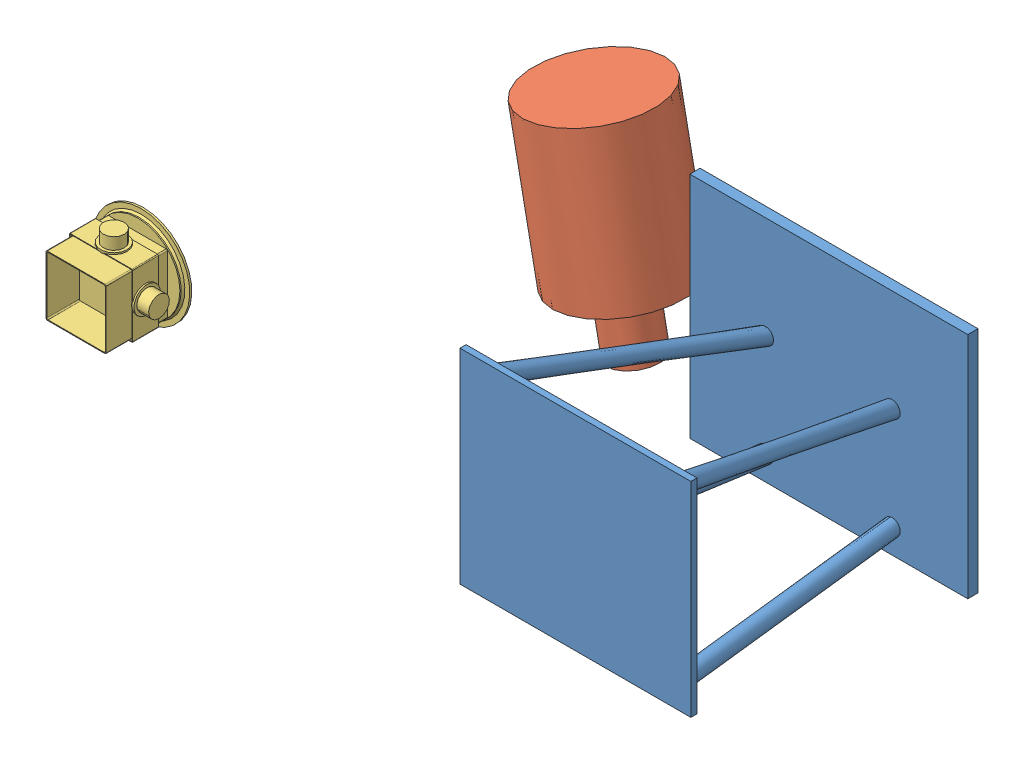
SolidWorks assembly Сборка1, configuration Default. Lengths in mm.
Overall size (1516.53 640.42 1145.63).
3 component instances, 3 part files, 2 mates.
Components (placement in the parent):
- Столик_3-1: Столик_3 [Default] at (296.4527 401.5534 802.29) size (680 560 645)
- Neutron_generator-1: Neutron_generator [Default] at (-428.6514 597.3112 32.29) x (0.748489 0.149038 0.646183) z (0.195284 -0.980747 0) size (300 300 525)
- detector9l_06102015-1: detector9l_06102015 [По умолчанию] at (-761.0802 443.3132 802.29) x (1 0 0) z (0 -1 0) size (238 164.23 238)
Mates (geometry in assembly coordinates):
- Касательность1: tangent aligned: plane of Столик_3-1 through (296.4527 401.5534 182.29) normal (0 0 1); cylinder of Neutron_generator-1 through (-355.4197 229.5312 32.29) axis (-0.195284 0.980747 0) radius 150
- Совпадение1: coincident anti-aligned: plane of Столик_3-1 through (296.4527 401.5534 802.29) normal (0 0 1); plane of detector9l_06102015-1 through (-761.0802 443.3132 802.29) normal (0 0 -1)
